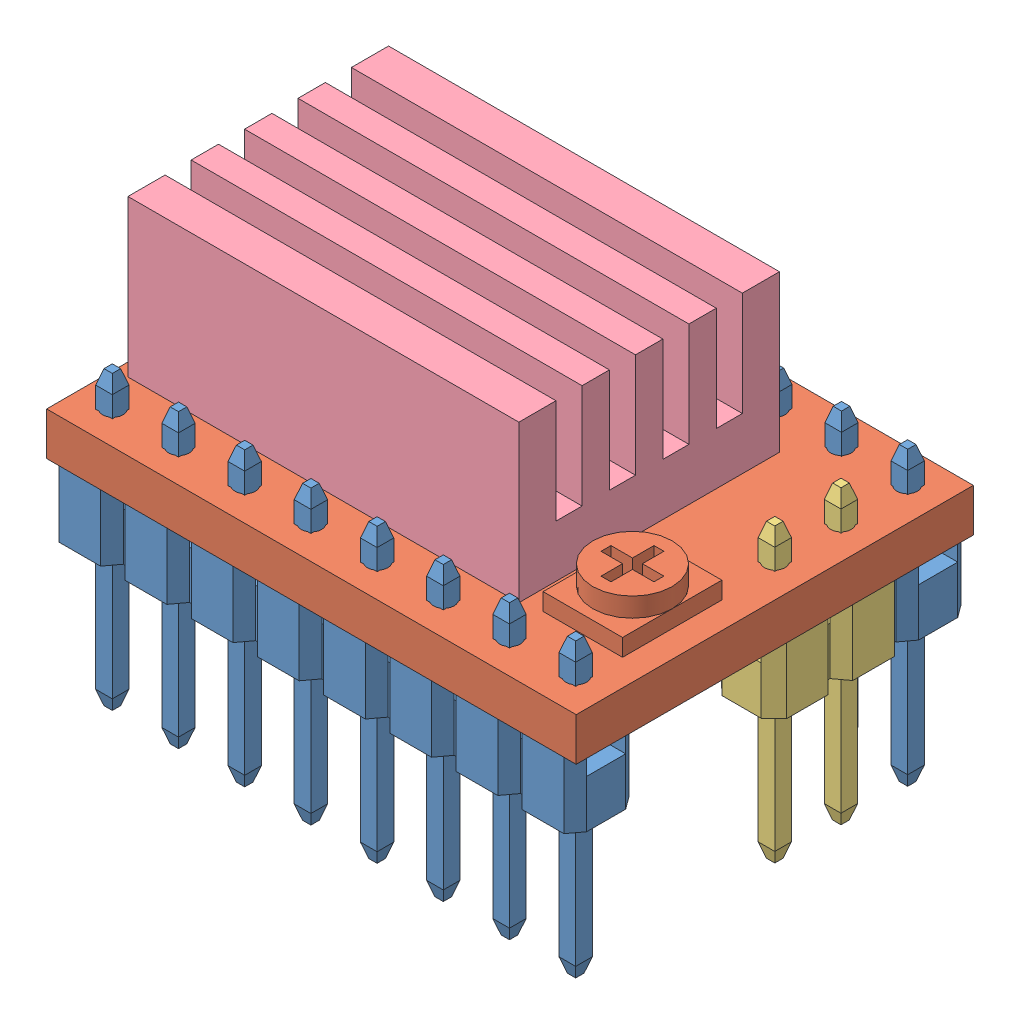
SolidWorks assembly Driver, configuration Default. Lengths in mm.
Overall size (20.32 15.85 15.24).
5 component instances, 4 part files, 15 mates.
Components (placement in the parent):
- pin_header_aw140-eg-g08d-1: pin_header_aw140-eg-g08d [Default] at (0 0 6.37) size (20.22 11.2 2.5)
- pin_header_aw140-eg-g08d-2: pin_header_aw140-eg-g08d [Default] at (0 0 -6.37) size (20.22 11.2 2.5)
- SD5984_PCB-1: SD5984_PCB [Default] at origin size (20.32 3.05 15.24)
- pin_header_aw140-eg-g02d-1: pin_header_aw140-eg-g02d [Default] at (8.89 0 -10.16) x (0 0 -1) z (1 0 0) size (5.08 11.2 2.5)
- Heatsink-1: Heatsink [Default] at (-9.66 1.651 0) x (0 0 -1) z (1 0 0) size (10 6 15)
Mates (geometry in assembly coordinates):
- Coincident42: coincident aligned: plane of SD5984_PCB-1 through (-10.16 1.651 7.62) normal (0 0 1); plane of pin_header_aw140-eg-g08d-1 through (-9.69 -2.54 7.62) normal (0 0 1)
- Coincident43: coincident aligned: plane of SD5984_PCB-1 through (-10.16 1.651 7.62) normal (-1 0 0); plane of pin_header_aw140-eg-g08d-1 through (-10.16 -2.54 7.12) normal (-1 0 0)
- Coincident44: coincident anti-aligned: plane of SD5984_PCB-1 through (0 0 0) normal (0 -1 0); plane of pin_header_aw140-eg-g08d-1 through (-7.72 0 7.62) normal (0 1 0)
- Coincident45: coincident aligned: plane of SD5984_PCB-1 through (-10.16 1.651 -7.62) normal (0 0 -1); plane of pin_header_aw140-eg-g08d-2 through (9.69 -2.54 -7.62) normal (0 0 -1)
- Coincident46: coincident aligned: plane of SD5984_PCB-1 through (-10.16 1.651 7.62) normal (-1 0 0); plane of pin_header_aw140-eg-g08d-2 through (-10.16 -2.54 -5.62) normal (-1 0 0)
- Coincident47: coincident anti-aligned: plane of SD5984_PCB-1 through (0 0 0) normal (0 -1 0); plane of pin_header_aw140-eg-g08d-2 through (-7.72 0 -5.12) normal (0 1 0)
- Coincident48: coincident aligned: plane of SD5984_PCB-1 through (0 0 0) normal (0 0 1); plane of assembly through (0 0 0) normal (0 0 1)
- Coincident49: coincident aligned: plane of SD5984_PCB-1 through (0 0 0) normal (0 1 0); plane of assembly through (0 0 0) normal (0 1 0)
- Coincident50: coincident aligned: plane of SD5984_PCB-1 through (0 0 0) normal (1 0 0); plane of assembly through (0 0 0) normal (1 0 0)
- Coincident51: coincident anti-aligned: plane of SD5984_PCB-1 through (0 0 0) normal (0 -1 0); plane of pin_header_aw140-eg-g02d-1 through (10.14 0 -2.44) normal (0 1 0)
- Concentric2: concentric aligned: cylinder of SD5984_PCB-1 through (8.89 -0.001 -1.27) axis (0 1 0) radius 0.3937; circle of pin_header_aw140-eg-g02d-1
- Concentric3: concentric aligned: cylinder of SD5984_PCB-1 through (8.89 -0.001 -3.81) axis (0 1 0) radius 0.3937; circle of pin_header_aw140-eg-g02d-1
- Coincident52: coincident anti-aligned: plane of Heatsink-1 through (-9.66 1.651 0) normal (0 0 -1); plane of assembly through (0 0 0) normal (0 0 1)
- Coincident53: coincident anti-aligned: plane of SD5984_PCB-1 through (0 1.651 0) normal (0 1 0); plane of Heatsink-1 through (5.34 1.651 0) normal (0 -1 0)
- Distance1: distance = 0.5 mm aligned: plane of Heatsink-1 through (-9.66 1.651 0) normal (-1 0 0); plane of SD5984_PCB-1 through (-10.16 1.651 7.62) normal (-1 0 0)
